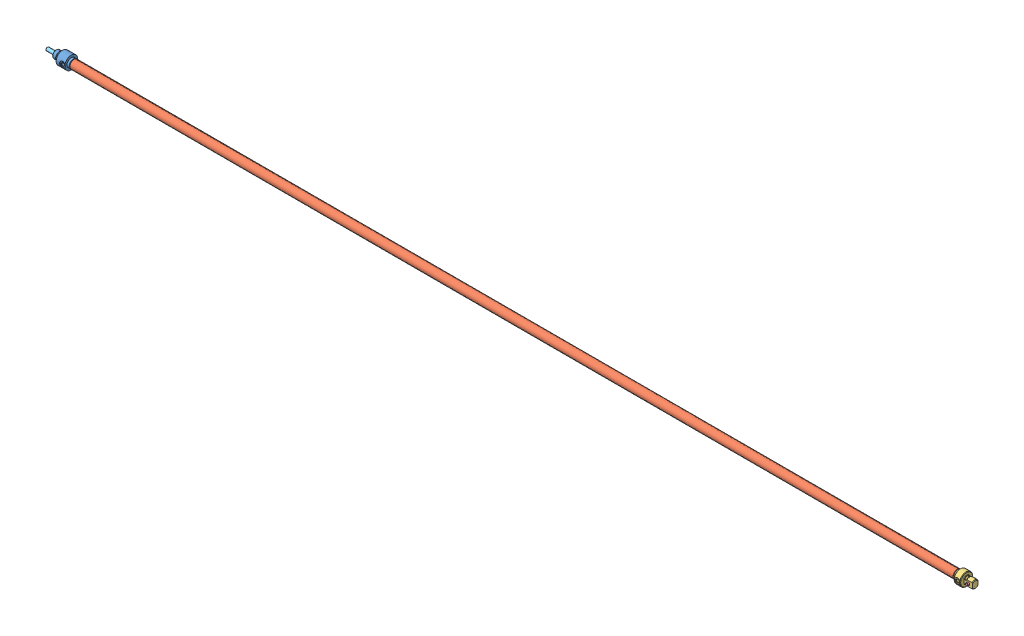
SolidWorks assembly 0150-DP, configuration Default. Lengths in mm.
Overall size (1354.07 18.75 18.75).
6 component instances, 6 part files, 14 mates.
Components (placement in the parent):
- 0150-DP0000_0_dummy-1: 0150-DP0000_0_dummy [Default] at origin
- 01R000-0_rod_guide-1: 01R000-0_rod_guide [Default] at origin size (30.18 18.75 18.75)
- 01R-50_770-1: 01R-50_770 [Default] at (25.908 0 0) size (1290.43 12.33 12.33)
- 01P1000_rear_head-1: 01P1000_rear_head [Default] at (1311.1988 0 0) size (30.18 18.75 18.75)
- D-787-1: D-787 [Default] at (1335.024 0 0) x (1 0 0) z (0 0 -1) size (3.97 3.97 12.7)
- 0150-DP0_rod-1: 0150-DP0_rod [Default] at origin size (1323.9 11.24 11.24)
Mates (geometry in assembly coordinates):
- Distance2: distance = 0 mm aligned: plane of 01R000-0_rod_guide-1 through (0 0 0) normal (1 0 0); plane of 0150-DP0000_0_dummy-1 through (0 0 0) normal (1 0 0)
- Coincident1: coincident aligned: line of 0150-DP0000_0_dummy-1 through (80.9 0 0) axis (-1 0 0); line of 01R000-0_rod_guide-1 through (80.9 0 0) axis (-1 0 0)
- Angle3: planar angle = 0 rad aligned: plane of 01R000-0_rod_guide-1 through (0 0 0) normal (0 0 -1); plane of 0150-DP0000_0_dummy-1 through (0 0 0) normal (0 0 -1)
- Distance4: distance = 0 mm aligned: plane of 01R-50_770-1 through (25.908 0 0) normal (1 0 0); plane of 01R000-0_rod_guide-1 through (25.908 0 0) normal (1 0 0)
- Coincident2: coincident aligned: line of 01R000-0_rod_guide-1 through (80.9 0 0) axis (-1 0 0); line of 01R-50_770-1 through (106.808 0 0) axis (-1 0 0)
- Angle6: planar angle = 0 rad aligned: plane of 01R-50_770-1 through (25.908 0 0) normal (0 0 -1); plane of 01R000-0_rod_guide-1 through (0 0 0) normal (0 0 -1)
- Distance6: distance = 0 mm aligned: plane of 01P1000_rear_head-1 through (1315.466 0 0) normal (1 0 0); plane of 01R-50_770-1 through (1315.466 0 0) normal (1 0 0)
- Coincident3: coincident aligned: line of 01R-50_770-1 through (106.808 0 0) axis (-1 0 0); line of 01P1000_rear_head-1 through (1392.0988 0 0) axis (-1 0 0)
- Angle9: planar angle = 0 rad aligned: plane of 01P1000_rear_head-1 through (1311.1988 0 0) normal (0 0 -1); plane of 01R-50_770-1 through (25.908 0 0) normal (0 0 -1)
- Distance7: distance = 0 mm anti-aligned: plane of D-787-1 through (1335.024 0 0) normal (0 0 -1); plane of 01P1000_rear_head-1 through (1311.1988 0 0) normal (0 0 1)
- Coincident4: coincident anti-aligned: line of 01P1000_rear_head-1 through (1335.024 0 80.9) axis (0 0 -1); line of D-787-1 through (1335.024 0 -80.9) axis (0 0 1)
- Angle12: planar angle = 0 rad aligned: plane of D-787-1; plane of 01P1000_rear_head-1 through (1335.024 0 0) normal (1 0 0)
- LimitDistance2: limit distance = 0 mm aligned: plane of 0150-DP0_rod-1 through (0 0 0) normal (1 0 0); plane of 01R000-0_rod_guide-1 through (0 0 0) normal (1 0 0)
- Coincident5: coincident aligned: line of 01R000-0_rod_guide-1 through (80.9 0 0) axis (-1 0 0); line of 0150-DP0_rod-1 through (80.9 0 0) axis (-1 0 0)
